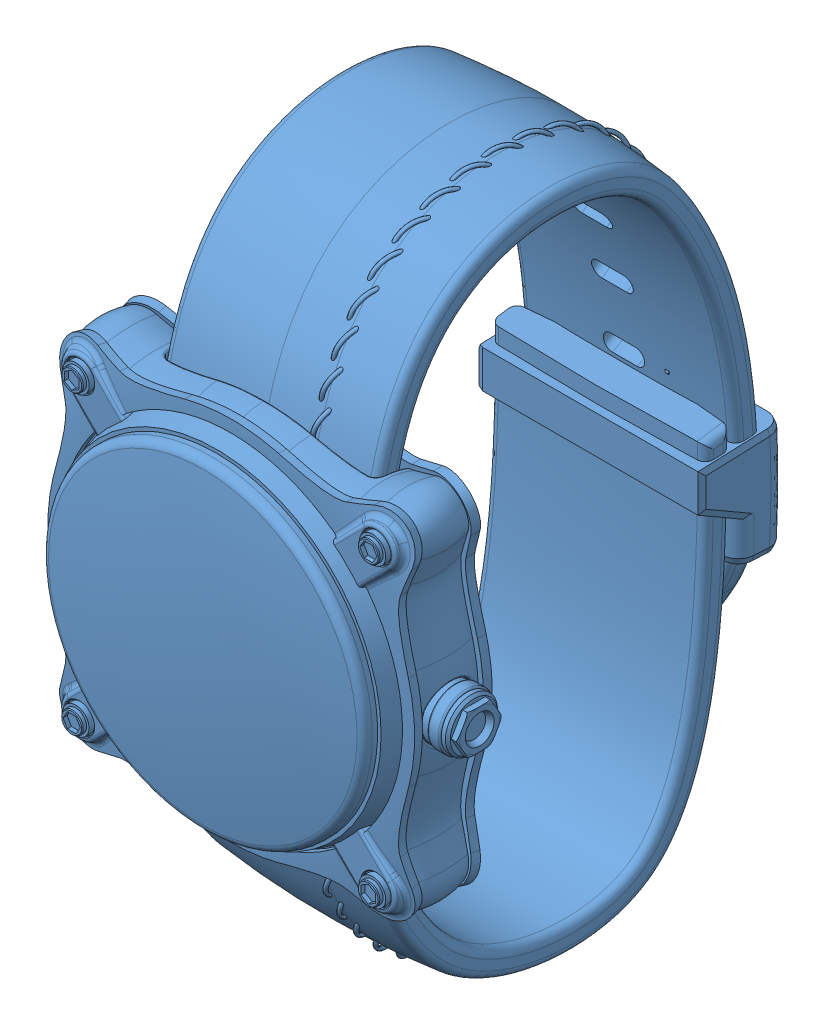
SolidWorks assembly Bomber watch, configuration Default. Lengths in mm.
Overall size (48.98 87.13 58.64).
7 component instances, 7 part files, 15 mates.
Components (placement in the parent):
- 1 - WWII bomber-1: 1 - WWII bomber [Default] at origin size (48.98 87.13 58.64)
- ETA 6497-1-1: ETA 6497-1 [Default] at (0 0 -0.6) x (1 0 0) z (0 -1 0) size (41.66 6.1 37.2)
- Second hand-1: Second hand [Default] at (-10.25 0 2.5) x (1 0 0) z (0 -1 0) size (7.3 0.3 7.85)
- Dial-1: Dial [Default] at (0 0 2) x (0 1 0) z (1 0 0) size (27.51 0.73 28.66)
- Hour hand-1: Hour hand [Default] at (0 0 2.85) x (0.623569 0.781768 0) z (0.781768 -0.623569 0) size (3.5 0.3 14.75)
- Minute hand-1: Minute hand [Default] at (0 0 3.4) x (0.616227 -0.787568 0) z (-0.787568 -0.616227 0) size (2 0.3 19)
- Caseback-1: Caseback [Default] at (0 0 -5) x (1 0 0) z (0 1 0) size (41 3.5 41)
Mates (geometry in assembly coordinates):
- Concentric1: concentric: cylinder of 1 - WWII bomber-1 through (0 0 3.75) axis (0 0 -1) radius 16; cylinder of ETA 6497-1-1 through (0 0 -2.2) axis (0 0 1) radius 18.15
- Coincident1: coincident: plane of 1 - WWII bomber-1 through (0 0 2) normal (0 0 -1); plane of ETA 6497-1-1 through (-9.3102 2.5383 2) normal (0 0 1)
- Concentric2: concentric: circle of ETA 6497-1-1; circle of Second hand-1
- Distance1: distance = 0.5 mm: plane of Second hand-1 through (-10.25 0 2.5) normal (0 0 -1); plane of ETA 6497-1-1 through (-9.3102 2.5383 2) normal (0 0 1)
- Coincident6: coincident: plane of ETA 6497-1-1 through (-9.3102 2.5383 2) normal (0 0 1); plane of Dial-1 through (-10.25 0 2) normal (0 0 -1)
- Concentric3: concentric anti-aligned: cylinder of 1 - WWII bomber-1 through (0 0 3.75) axis (0 0 -1) radius 16; circle of Dial-1
- Coincident7: coincident aligned: plane of Dial-1; plane of assembly through (0 0 0) normal (0 1 0)
- Concentric4: concentric anti-aligned: circle of 1 - WWII bomber-1; circle of Second hand-1
- Parallel1: parallel aligned: plane of Second hand-1; plane of assembly through (0 0 0) normal (1 0 0)
- Concentric5: concentric aligned: cylinder of 1 - WWII bomber-1 through (0 0 -5) axis (0 0 1) radius 18.25; cylinder of Caseback-1 through (0 0 -5) axis (0 0 1) radius 20.5
- Coincident8: coincident anti-aligned: plane of 1 - WWII bomber-1 through (0 0 -5) normal (0 0 -1); plane of Caseback-1 through (0 -16 -5) normal (0 0 1)
- Concentric6: concentric: circle of ETA 6497-1-1; circle of Hour hand-1
- Concentric7: concentric: circle of ETA 6497-1-1; circle of Minute hand-1; plane of Minute hand-1; plane of ETA 6497-1-1; plane of Hour hand-1; plane of ETA 6497-1-1
- Distance2: distance = 0.1 mm: plane of Minute hand-1 through (0 0 3.4) normal (0 0 -1); plane of ETA 6497-1-1 through (-0.9499 0.0158 3.3) normal (0 0 1)
- Distance3: distance = 0.9 mm: plane of Hour hand-1 through (0 0 2.85) normal (0 0 -1); plane of ETA 6497-1-1 through (-3.6745 0.0612 1.95) normal (0 0 1)
